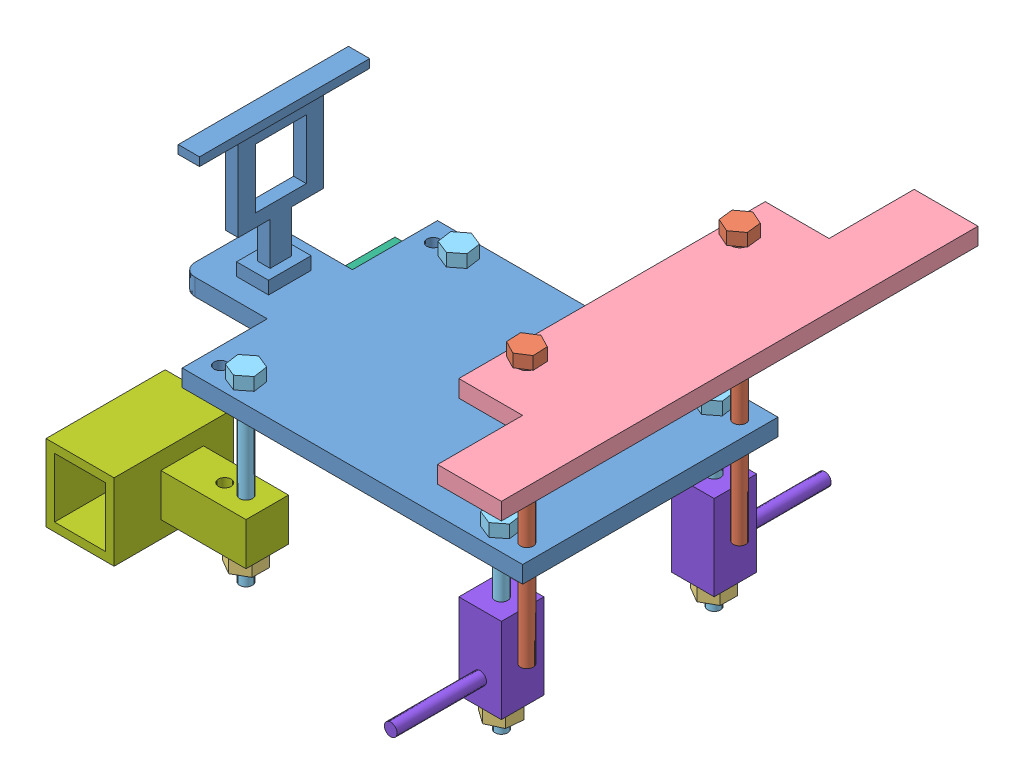
SolidWorks assembly Assembly1, configuration Default. Lengths in mm.
Overall size (122 81.35 112).
16 component instances, 8 part files, 33 mates.
Components (placement in the parent):
- Part1Fโครงรถ-1: Part1Fโครงรถ [Default] at (54.4173 41.143 84.6953) size (100 39 60)
- Part2น็อตประกอบชิ้นส่วนด้านบน-1: Part2น็อตประกอบชิ้นส่วนด้านบน [Default] at (76.3483 82.4967 49.6953) x (1 0 0) z (0 1 0) size (6.35 6.88 65)
- Part2น็อตปิด-1: Part2น็อตปิด [Default] at (10.3483 7.7866 99.6953) x (1 0 0) z (0 1 0) size (7.03 8.08 4)
- Part3ชิ้นส่วนด้านบน-1: Part3ชิ้นส่วนด้านบน [Default] at (87.6891 77.4967 70.8741) x (0 0 1) z (-1 0 0) size (112 4 30)
- Part4น็อตประกอบชิ้นส่วนล้อ-1: Part4น็อตประกอบชิ้นส่วนล้อ [Default] at (10.3483 48.143 99.6953) x (1 0 0) z (0 -1 0) size (6.43 6.86 44)
- Part5ชิ้นส่วนประกอบมอเตอร์ด้านหน้า1-1: Part5ชิ้นส่วนประกอบมอเตอร์ด้านหน้า1 [Default] at (-15.2978 7.7866 48.1569) x (0 0 -1) z (1 0 0) size (28 18 36)
- Part5ชิ้นส่วนประกอบมอเตอร์ด้านหน้า2-1: Part5ชิ้นส่วนประกอบมอเตอร์ด้านหน้า2 [Default] at (-15.2978 7.7866 102.1569) x (0 0 -1) z (1 0 0) size (28 18 36)
- Part6ชิ้นส่วนประกอบมอเตอร์ด้านหลัง-1: Part6ชิ้นส่วนประกอบมอเตอร์ด้านหลัง [Default] at (70.3201 28.5605 94.6953) x (1 0 0) z (0 -1 0) size (10 31 20)
- Part2น็อตประกอบชิ้นส่วนด้านบน-2: Part2น็อตประกอบชิ้นส่วนด้านบน [Default] at (76.3483 82.4967 99.6953) x (0.997654 0 0.06846) z (0 1 0) size (6.35 6.88 65)
- Part4น็อตประกอบชิ้นส่วนล้อ-2: Part4น็อตประกอบชิ้นส่วนล้อ [Default] at (10.3483 48.143 49.6953) x (1 0 0) z (0 -1 0) size (6.43 6.86 44)
- Part4น็อตประกอบชิ้นส่วนล้อ-3: Part4น็อตประกอบชิ้นส่วนล้อ [Default] at (70.3483 48.143 49.6953) x (1 0 0) z (0 -1 0) size (6.43 6.86 44)
- Part4น็อตประกอบชิ้นส่วนล้อ-4: Part4น็อตประกอบชิ้นส่วนล้อ [Default] at (70.3483 48.143 99.6953) x (1 0 0) z (0 -1 0) size (6.43 6.86 44)
- Part6ชิ้นส่วนประกอบมอเตอร์ด้านหลัง-2: Part6ชิ้นส่วนประกอบมอเตอร์ด้านหลัง [Default] at (70.3766 28.5605 54.6953) x (-1 0 0) z (0 -1 0) size (10 31 20)
- Part2น็อตปิด-2: Part2น็อตปิด [Default] at (10.3483 7.7866 49.6953) x (1 0 0) z (0 1 0) size (7.03 8.08 4)
- Part2น็อตปิด-3: Part2น็อตปิด [Default] at (70.3483 7.0747 49.6953) x (1 0 0) z (0 1 0) size (7.03 8.08 4)
- Part2น็อตปิด-4: Part2น็อตปิด [Default] at (70.3483 7.0747 99.6953) x (0.99629 0 0.086057) z (0 1 0) size (7.03 8.08 4)
Mates (geometry in assembly coordinates):
- Concentric1: concentric aligned: circle of Part1Fโครงรถ-1; circle of Part3ชิ้นส่วนด้านบน-1
- Concentric2: concentric aligned: circle of Part1Fโครงรถ-1; circle of Part3ชิ้นส่วนด้านบน-1
- Concentric3: concentric anti-aligned: circle of Part2น็อตประกอบชิ้นส่วนด้านบน-1; circle of Part3ชิ้นส่วนด้านบน-1
- Coincident4: coincident anti-aligned: plane of Part2น็อตประกอบชิ้นส่วนด้านบน-1 through (76.3483 81.4967 49.6953) normal (0 -1 0); plane of Part3ชิ้นส่วนด้านบน-1 through (87.6891 81.4967 70.8741) normal (0 1 0)
- Concentric4: concentric anti-aligned: circle of Part1Fโครงรถ-1; circle of Part4น็อตประกอบชิ้นส่วนล้อ-1
- Coincident6: coincident anti-aligned: plane of Part1Fโครงรถ-1 through (-16.6517 45.143 81.6953) normal (0 1 0); plane of Part4น็อตประกอบชิ้นส่วนล้อ-1 through (10.3483 45.143 99.6953) normal (0 -1 0)
- Concentric5: concentric anti-aligned: circle of Part3ชิ้นส่วนด้านบน-1; circle of Part2น็อตประกอบชิ้นส่วนด้านบน-2
- Coincident8: coincident anti-aligned: plane of Part3ชิ้นส่วนด้านบน-1 through (87.6891 81.4967 70.8741) normal (0 1 0); plane of Part2น็อตประกอบชิ้นส่วนด้านบน-2 through (76.3483 81.4967 99.6953) normal (0 -1 0)
- Concentric6: concentric anti-aligned: circle of Part1Fโครงรถ-1; circle of Part4น็อตประกอบชิ้นส่วนล้อ-2
- Coincident10: coincident anti-aligned: plane of Part1Fโครงรถ-1 through (-16.6517 45.143 81.6953) normal (0 1 0); plane of Part4น็อตประกอบชิ้นส่วนล้อ-2 through (10.3483 45.143 49.6953) normal (0 -1 0)
- Concentric7: concentric anti-aligned: circle of Part1Fโครงรถ-1; circle of Part4น็อตประกอบชิ้นส่วนล้อ-3
- Coincident12: coincident anti-aligned: plane of Part1Fโครงรถ-1 through (-16.6517 45.143 81.6953) normal (0 1 0); plane of Part4น็อตประกอบชิ้นส่วนล้อ-3 through (70.3483 45.143 49.6953) normal (0 -1 0)
- Concentric8: concentric anti-aligned: circle of Part1Fโครงรถ-1; circle of Part4น็อตประกอบชิ้นส่วนล้อ-4
- Coincident14: coincident anti-aligned: plane of Part1Fโครงรถ-1 through (-16.6517 45.143 81.6953) normal (0 1 0); plane of Part4น็อตประกอบชิ้นส่วนล้อ-4 through (70.3483 45.143 99.6953) normal (0 -1 0)
- Concentric10: concentric anti-aligned: circle of Part6ชิ้นส่วนประกอบมอเตอร์ด้านหลัง-1; circle of Part4น็อตประกอบชิ้นส่วนล้อ-4
- Concentric11: concentric anti-aligned: circle of Part4น็อตประกอบชิ้นส่วนล้อ-3; circle of Part6ชิ้นส่วนประกอบมอเตอร์ด้านหลัง-2
- Parallel1: parallel aligned: plane of Part1Fโครงรถ-1 through (80.3483 45.143 44.6953) normal (1 0 0); plane of Part6ชิ้นส่วนประกอบมอเตอร์ด้านหลัง-2 through (75.3483 31.0747 44.6953) normal (1 0 0)
- Parallel2: parallel aligned: plane of Part1Fโครงรถ-1 through (80.3483 45.143 44.6953) normal (1 0 0); plane of Part6ชิ้นส่วนประกอบมอเตอร์ด้านหลัง-1 through (75.3483 31.0747 104.6953) normal (1 0 0)
- Concentric12: concentric anti-aligned: circle of Part4น็อตประกอบชิ้นส่วนล้อ-1; circle of Part5ชิ้นส่วนประกอบมอเตอร์ด้านหน้า2-1
- Coincident19: coincident aligned: plane of Part1Fโครงรถ-1 through (80.3483 45.143 104.6953) normal (0 0 1); plane of Part5ชิ้นส่วนประกอบมอเตอร์ด้านหน้า2-1 through (15.3483 21.7866 104.6953) normal (0 0 1)
- Concentric13: concentric anti-aligned: circle of Part2น็อตปิด-1; circle of Part4น็อตประกอบชิ้นส่วนล้อ-1
- Coincident22: coincident anti-aligned: plane of Part2น็อตปิด-1 through (10.3483 11.7866 99.6953) normal (0 1 0); plane of Part5ชิ้นส่วนประกอบมอเตอร์ด้านหน้า2-1 through (15.3483 11.7866 104.6953) normal (0 -1 0)
- Concentric15: concentric anti-aligned: circle of Part5ชิ้นส่วนประกอบมอเตอร์ด้านหน้า1-1; circle of Part4น็อตประกอบชิ้นส่วนล้อ-2
- Parallel5: parallel anti-aligned: plane of Part1Fโครงรถ-1 through (0.3483 45.143 44.6953) normal (0 0 -1); plane of Part5ชิ้นส่วนประกอบมอเตอร์ด้านหน้า1-1 through (-20.6517 25.7866 61.6953) normal (0 0 1)
- Parallel6: parallel aligned: plane of Part1Fโครงรถ-1 through (0.3483 45.143 44.6953) normal (0 0 -1); plane of Part5ชิ้นส่วนประกอบมอเตอร์ด้านหน้า1-1 through (15.3483 21.7866 44.6953) normal (0 0 -1)
- Concentric16: concentric anti-aligned: circle of Part4น็อตประกอบชิ้นส่วนล้อ-2; circle of Part2น็อตปิด-2
- Coincident31: coincident anti-aligned: plane of Part5ชิ้นส่วนประกอบมอเตอร์ด้านหน้า1-1 through (15.3483 11.7866 54.6953) normal (0 -1 0); plane of Part2น็อตปิด-2 through (10.3483 11.7866 49.6953) normal (0 1 0)
- Coincident32: coincident aligned: plane of Part6ชิ้นส่วนประกอบมอเตอร์ด้านหลัง-1 through (65.3483 11.0747 104.6953) normal (0 -1 0); plane of Part6ชิ้นส่วนประกอบมอเตอร์ด้านหลัง-2 through (75.3483 11.0747 44.6953) normal (0 -1 0)
- Coincident33: coincident aligned: plane of Part5ชิ้นส่วนประกอบมอเตอร์ด้านหน้า1-1 through (-15.2978 7.7866 48.1569) normal (0 -1 0); plane of Part5ชิ้นส่วนประกอบมอเตอร์ด้านหน้า2-1 through (-15.2978 7.7866 102.1569) normal (0 -1 0)
- Concentric17: concentric anti-aligned: circle of Part4น็อตประกอบชิ้นส่วนล้อ-3; circle of Part2น็อตปิด-3
- Coincident35: coincident anti-aligned: plane of Part6ชิ้นส่วนประกอบมอเตอร์ด้านหลัง-2 through (75.3483 11.0747 44.6953) normal (0 -1 0); plane of Part2น็อตปิด-3 through (70.3483 11.0747 49.6953) normal (0 1 0)
- Concentric18: concentric anti-aligned: circle of Part4น็อตประกอบชิ้นส่วนล้อ-4; circle of Part2น็อตปิด-4
- Coincident37: coincident anti-aligned: plane of Part6ชิ้นส่วนประกอบมอเตอร์ด้านหลัง-1 through (65.3483 11.0747 104.6953) normal (0 -1 0); plane of Part2น็อตปิด-4 through (70.3483 11.0747 99.6953) normal (0 1 0)
